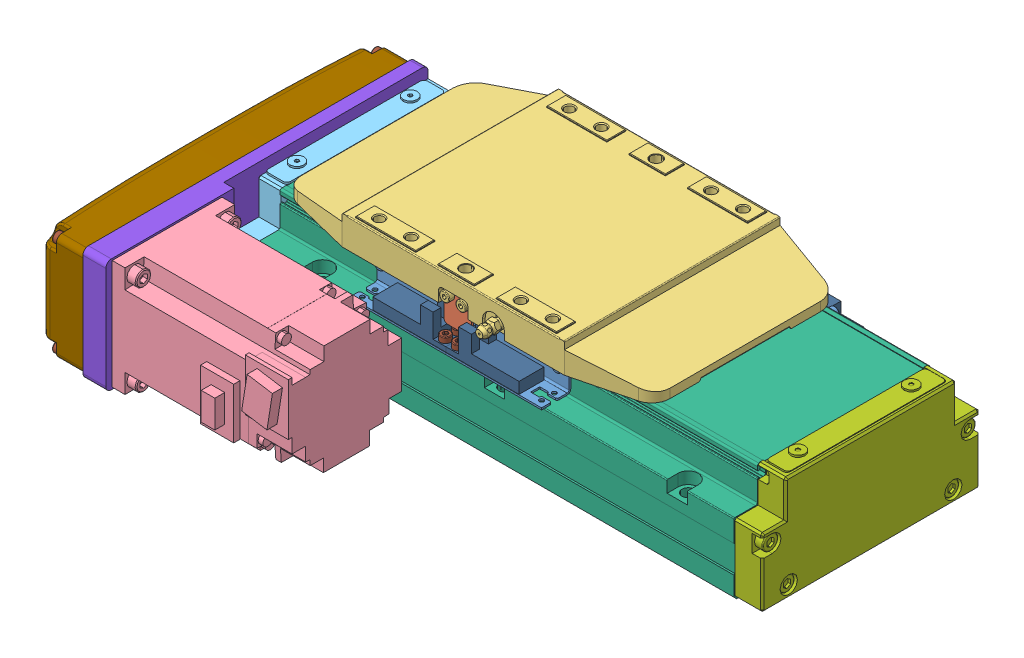
SolidWorks assembly G12-BL-400W, configuration Default. Lengths in mm.
Overall size (320.5 76 207.1).
25 component instances, 11 part files, 62 mates.
Components (placement in the parent):
- 304开关座片G5-12^G12-BL-400W-1: 304开关座片G5-12^G12-BL-400W [Default] at (209 38.5 -47.2) x (-1 0 0) z (0 0 -1) size (52.5 15.7 21) (virtual)
- 304开关座片G5-12^G12-BL-400W-2: 304开关座片G5-12^G12-BL-400W [Default] at (54 38.5 47.2) size (52.5 15.7 21) (virtual)
- 304开关座片G5-12^G12-BL-400W-3: 304开关座片G5-12^G12-BL-400W [Default] at (106.5 38.5 47.2) size (52.5 15.7 21) (virtual)
- 304感应片G8-12^G12-BL-400W-1: 304感应片G8-12^G12-BL-400W [Default] at (106.5 56.7 0) x (1 0 0) z (0 0 -1) size (15 17 1) (virtual)
- 304感应片G8-12^G12-BL-400W-2: 304感应片G8-12^G12-BL-400W [Default] at (106.5 56.7 0) x (-1 0 0) z (0 0 1) size (15 17 1) (virtual)
- 滑台G12^G12-BL-400W-1: 滑台G12^G12-BL-400W [Default] at (106.5 59.3 0) size (201.5 16.7 133.6) (virtual)
- 三菱400w^G12-BL-400W-1: 三菱400w^G12-BL-400W [Default] at (-7.5 32.5 101.5) x (0 0 1) z (0 1 0) size (68.8 128.3 60) (virtual)
- 丝杆座板G12^G12-BL-400W-1: 丝杆座板G12^G12-BL-400W [Default] at origin size (20.5 58.7 119) (virtual)
- 复件 复件 底座GY12+211^G12-BL-400W-1: 复件 复件 底座GY12+211^G12-BL-400W [默认] x (0 0 -1) z (1 0 0) size (120 58 261) (virtual)
- 塑胶轴承座G12^G12-BL-400W-2: 塑胶轴承座G12^G12-BL-400W [Default] at (261 0 0) size (15 58.9 119) (virtual)
- 电机板G12-BLR-P60^G12-BL-400W-1: 电机板G12-BLR-P60^G12-BL-400W [Default] at origin size (12.5 62 181.75) (virtual)
- 复件 同步轮罩壳G12^G12-BL-400W-1: 复件 同步轮罩壳G12^G12-BL-400W [默认] at (-43.3 32.5 44.125) x (0 0 1) z (0 1 0) size (180.75 24.5 61.51) (virtual)
- 复件 光电开关EE-SX674^G12-BL-400W-1: 复件 光电开关EE-SX674^G12-BL-400W [默认] at (66.5 41.8 49.4) size (40 15.5 13.6) (virtual)
- 复件 光电开关EE-SX674^G12-BL-400W-2: 复件 光电开关EE-SX674^G12-BL-400W [默认] at (146.5 41.8 63) x (-1 0 0) z (0 0 -1) size (40 15.5 13.6) (virtual)
- 复件 光电开关EE-SX674^G12-BL-400W-3: 复件 光电开关EE-SX674^G12-BL-400W [默认] at (196.5 41.8 -49.4) x (-1 0 0) z (0 0 -1) size (40 15.5 13.6) (virtual)
- hexagon socket head cap screws gb-1: hexagon socket head cap screws gb [GB_FASTENER_SCREWS_HSHCS M3X5-N] at (103 47.4 59.7) x (0 -1 0) z (0 0 1) size (8 5.5 5.5)
- hexagon socket head cap screws gb-2: hexagon socket head cap screws gb [GB_FASTENER_SCREWS_HSHCS M3X5-N] at (110 47.4 59.7) x (0 -1 0) z (0 0 1) size (8 5.5 5.5)
- hexagon socket head cap screws gb-3: hexagon socket head cap screws gb [GB_FASTENER_SCREWS_HSHCS M3X5-N] at (103 47.4 52.7) x (0 -1 0) z (0 0 1) size (8 5.5 5.5)
- hexagon socket head cap screws gb-4: hexagon socket head cap screws gb [GB_FASTENER_SCREWS_HSHCS M3X5-N] at (110 47.4 52.7) x (0 -1 0) z (0 0 1) size (8 5.5 5.5)
- hexagon socket head cap screws gb-6: hexagon socket head cap screws gb [GB_FASTENER_SCREWS_HSHCS M3X5-N] at (160 47.4 -59.7) x (0 -1 0) z (0 0 1) size (8 5.5 5.5)
- hexagon socket head cap screws gb-7: hexagon socket head cap screws gb [GB_FASTENER_SCREWS_HSHCS M3X5-N] at (160 47.4 -52.7) x (0 -1 0) z (0 0 1) size (8 5.5 5.5)
- hexagon socket head cap screws gb-8: hexagon socket head cap screws gb [GB_FASTENER_SCREWS_HSHCS M3X20-N] at (-38 58.5 131.125) size (23 5.5 5.5)
- hexagon socket head cap screws gb-9: hexagon socket head cap screws gb [GB_FASTENER_SCREWS_HSHCS M3X20-N] at (-38 6.5 131.125) size (23 5.5 5.5)
- hexagon socket head cap screws gb-10: hexagon socket head cap screws gb [GB_FASTENER_SCREWS_HSHCS M3X20-N] at (-38 6.5 -42.875) size (23 5.5 5.5)
- hexagon socket head cap screws gb-11: hexagon socket head cap screws gb [GB_FASTENER_SCREWS_HSHCS M3X20-N] at (-38 58.5 -42.875) size (23 5.5 5.5)
Mates (geometry in assembly coordinates):
- 宽度3: width: plane of 丝杆座板G12^G12-BL-400W-1 through (-13 37.5 59.5) normal (0 0 1); plane of 丝杆座板G12^G12-BL-400W-1 through (-13 2 -59.5) normal (0 0 -1); plane of 复件 复件 底座GY12+211^G12-BL-400W-1 through (261 12.5 -59.5) normal (0 0 -1); plane of 复件 复件 底座GY12+211^G12-BL-400W-1 through (261 26.5 59.5) normal (0 0 1)
- 距离2: distance = 1 mm: plane of 复件 复件 底座GY12+211^G12-BL-400W-1 through (261 0 58.5) normal (0 -1 0); plane of 丝杆座板G12^G12-BL-400W-1 through (-13 1 58.5) normal (0 -1 0)
- 重合11: coincident: plane of 丝杆座板G12^G12-BL-400W-1 through (0 0 0) normal (1 0 0); plane of 复件 复件 底座GY12+211^G12-BL-400W-1 through (0 57 46.2) normal (-1 0 0)
- 宽度8: width: plane of 滑台G12^G12-BL-400W-1 through (45.75 76 59) normal (0 0 1); plane of 滑台G12^G12-BL-400W-1 through (167.25 76 -59) normal (0 0 -1); plane of 复件 复件 底座GY12+211^G12-BL-400W-1 through (261 12.5 -59.5) normal (0 0 -1); plane of 复件 复件 底座GY12+211^G12-BL-400W-1 through (261 26.5 59.5) normal (0 0 1)
- 距离5: distance = 76 mm: plane of 滑台G12^G12-BL-400W-1 through (15.75 76 -41.214) normal (0 1 0); plane of 复件 复件 底座GY12+211^G12-BL-400W-1 through (261 0 58.5) normal (0 -1 0)
- 宽度9: width: plane of 304感应片G8-12^G12-BL-400W-2 through (99 64 56.5) normal (-1 0 0); plane of 304感应片G8-12^G12-BL-400W-2 through (114 51 56.5) normal (1 0 0); plane of 滑台G12^G12-BL-400W-1 through (98.5 65 55.5) normal (1 0 0); plane of 滑台G12^G12-BL-400W-1 through (114.5 59.3 55.5) normal (-1 0 0)
- 距离6: distance = 10.3 mm: plane of 304感应片G8-12^G12-BL-400W-2 through (101 49 56.5) normal (0 -1 0); plane of 滑台G12^G12-BL-400W-1 through (15.75 59.3 -41.214) normal (0 -1 0)
- 距离7: distance = 2.5 mm: plane of 304感应片G8-12^G12-BL-400W-2 through (112 51 56.5) normal (0 0 1); plane of 滑台G12^G12-BL-400W-1 through (45.75 76 59) normal (0 0 1)
- 宽度10: width: plane of 304感应片G8-12^G12-BL-400W-1 through (99 51 -56.5) normal (-1 0 0); plane of 304感应片G8-12^G12-BL-400W-1 through (114 64 -56.5) normal (1 0 0); plane of 滑台G12^G12-BL-400W-1 through (98.5 65 -55.5) normal (1 0 0); plane of 滑台G12^G12-BL-400W-1 through (114.5 59.3 -55.5) normal (-1 0 0)
- 距离8: distance = 2.5 mm: plane of 304感应片G8-12^G12-BL-400W-1 through (101 51 -56.5) normal (0 0 -1); plane of 滑台G12^G12-BL-400W-1 through (167.25 76 -59) normal (0 0 -1)
- 距离9: distance = 10.3 mm: plane of 304感应片G8-12^G12-BL-400W-1 through (112 49 -56.5) normal (0 -1 0); plane of 滑台G12^G12-BL-400W-1 through (15.75 59.3 -41.214) normal (0 -1 0)
- 宽度14: width: plane of 塑胶轴承座G12^G12-BL-400W-2 through (276 37.5 59.5) normal (0 0 1); plane of 塑胶轴承座G12^G12-BL-400W-2 through (276 2 -59.5) normal (0 0 -1); plane of 复件 复件 底座GY12+211^G12-BL-400W-1 through (261 12.5 -59.5) normal (0 0 -1); plane of 复件 复件 底座GY12+211^G12-BL-400W-1 through (261 26.5 59.5) normal (0 0 1)
- 重合23: coincident: plane of 复件 复件 底座GY12+211^G12-BL-400W-1 through (261 57 46.2) normal (1 0 0); plane of 塑胶轴承座G12^G12-BL-400W-2 through (261 0 0) normal (-1 0 0)
- 距离10: distance = 1 mm: plane of 塑胶轴承座G12^G12-BL-400W-2 through (276 1 58.5) normal (0 -1 0); plane of 复件 复件 底座GY12+211^G12-BL-400W-1 through (261 0 58.5) normal (0 -1 0)
- 距离11: distance = 67 mm: plane of 304开关座片G5-12^G12-BL-400W-2 through (54 42.8 49.2) normal (-1 0 0); plane of 丝杆座板G12^G12-BL-400W-1 through (-13 0 0) normal (-1 0 0)
- 距离12: distance = 105 mm: plane of 304开关座片G5-12^G12-BL-400W-3 through (159 42.8 49.2) normal (1 0 0); plane of 304开关座片G5-12^G12-BL-400W-2 through (54 42.8 49.2) normal (-1 0 0)
- 宽度15: width: plane of 复件 复件 底座GY12+211^G12-BL-400W-1 through (261 51.25 46.2) normal (0 1 0); plane of 复件 复件 底座GY12+211^G12-BL-400W-1 through (261 54.75 46.7) normal (0 -1 0); cylinder of 304开关座片G5-12^G12-BL-400W-2 through (58 53 42.2) axis (0 0 -1) radius 2.75
- 重合28: coincident: plane of 304开关座片G5-12^G12-BL-400W-2 through (106.5 40.8 63.2) normal (0 -1 0); plane of 304开关座片G5-12^G12-BL-400W-3 through (159 40.8 63.2) normal (0 -1 0)
- 重合29: coincident: plane of 304开关座片G5-12^G12-BL-400W-2 through (106.5 56.5 48.2) normal (0 0 1); plane of 304开关座片G5-12^G12-BL-400W-3 through (159 56.5 48.2) normal (0 0 1)
- 重合30: coincident: plane of 304开关座片G5-12^G12-BL-400W-2 through (106.5 42.8 47.2) normal (0 0 -1); plane of 复件 复件 底座GY12+211^G12-BL-400W-1 through (261 50.75 47.2) normal (0 0 1)
- 宽度16: width: plane of 复件 复件 底座GY12+211^G12-BL-400W-1 through (261 51.25 -46.7) normal (0 1 0); plane of 复件 复件 底座GY12+211^G12-BL-400W-1 through (261 54.75 -46.2) normal (0 -1 0); cylinder of 304开关座片G5-12^G12-BL-400W-1 through (205 53 -42.2) axis (0 0 1) radius 2.75
- 重合36: coincident: plane of 304开关座片G5-12^G12-BL-400W-1 through (156.5 42.8 -47.2) normal (0 0 1); plane of 复件 复件 底座GY12+211^G12-BL-400W-1 through (261 40 -47.2) normal (0 0 -1)
- 距离15: distance = 12.75 mm: plane of 电机板G12-BLR-P60^G12-BL-400W-1 through (-59.5 4.5 -46.75) normal (0 0 -1); plane of 复件 复件 底座GY12+211^G12-BL-400W-1 through (261 12.5 -59.5) normal (0 0 -1)
- 距离16: distance = 1.5 mm: plane of 电机板G12-BLR-P60^G12-BL-400W-1 through (-59.5 1.5 132) normal (0 -1 0); plane of 复件 复件 底座GY12+211^G12-BL-400W-1 through (261 0 -35) normal (0 -1 0)
- 重合39: coincident: plane of 丝杆座板G12^G12-BL-400W-1 through (-13 0 0) normal (-1 0 0); plane of 电机板G12-BLR-P60^G12-BL-400W-1 through (-13 4.5 132) normal (1 0 0)
- 距离17: distance = 11.5 mm: plane of 三菱400w^G12-BL-400W-1 through (67 2.5 71.5) normal (0 0 -1); plane of 复件 复件 底座GY12+211^G12-BL-400W-1 through (261 38.5 60) normal (0 0 1)
- 宽度22: width: plane of 电机板G12-BLR-P60^G12-BL-400W-1 through (-59.5 1.5 132) normal (0 -1 0); plane of 电机板G12-BLR-P60^G12-BL-400W-1 through (-59.5 63.5 -43.75) normal (0 1 0); plane of 三菱400w^G12-BL-400W-1 through (67 62.5 71.5) normal (0 1 0); plane of 三菱400w^G12-BL-400W-1 through (67 2.5 131.5) normal (0 -1 0)
- 重合43: coincident: plane of 三菱400w^G12-BL-400W-1 through (-7.5 32.5 101.5) normal (-1 0 0); plane of 电机板G12-BLR-P60^G12-BL-400W-1 through (-7.5 4.5 132) normal (1 0 0)
- 宽度23: width: plane of 304开关座片G5-12^G12-BL-400W-2 through (54 42.8 49.2) normal (-1 0 0); plane of 304开关座片G5-12^G12-BL-400W-3 through (159 42.8 49.2) normal (1 0 0); plane of 304感应片G8-12^G12-BL-400W-2 through (99 64 56.5) normal (-1 0 0); plane of 304感应片G8-12^G12-BL-400W-2 through (114 51 56.5) normal (1 0 0)
- 距离18: distance = 67 mm: plane of 304开关座片G5-12^G12-BL-400W-1 through (209 42.8 -49.2) normal (1 0 0); plane of 塑胶轴承座G12^G12-BL-400W-2 through (276 0 0) normal (1 0 0)
- 重合44: coincident: plane of 304开关座片G5-12^G12-BL-400W-2 through (106.5 41.8 49.2) normal (0 1 0); plane of 复件 光电开关EE-SX674^G12-BL-400W-1 through (106.5 41.8 63) normal (0 -1 0)
- 同心7: concentric: cylinder of 304开关座片G5-12^G12-BL-400W-2 through (103 43.5 52.7) axis (0 -1 0) radius 1.23; cylinder of 复件 光电开关EE-SX674^G12-BL-400W-1 through (103 30.8 52.7) axis (0 1 0) radius 1.75
- 同心8: concentric: cylinder of 304开关座片G5-12^G12-BL-400W-2 through (103 43.5 59.7) axis (0 -1 0) radius 1.23; cylinder of 复件 光电开关EE-SX674^G12-BL-400W-1 through (103 30.8 59.7) axis (0 1 0) radius 1.75
- 同心9: concentric: cylinder of 304开关座片G5-12^G12-BL-400W-3 through (110 43.5 59.7) axis (0 -1 0) radius 1.23; cylinder of 复件 光电开关EE-SX674^G12-BL-400W-2 through (110 30.8 59.7) axis (0 1 0) radius 1.75
- 重合45: coincident: plane of 304开关座片G5-12^G12-BL-400W-3 through (159 41.8 49.2) normal (0 1 0); plane of 复件 光电开关EE-SX674^G12-BL-400W-2 through (106.5 41.8 49.4) normal (0 -1 0)
- 同心10: concentric: cylinder of 304开关座片G5-12^G12-BL-400W-3 through (110 43.5 52.7) axis (0 -1 0) radius 1.23; cylinder of 复件 光电开关EE-SX674^G12-BL-400W-2 through (110 30.8 52.7) axis (0 1 0) radius 1.75
- 重合46: coincident: plane of 304开关座片G5-12^G12-BL-400W-1 through (156.5 41.8 -49.2) normal (0 1 0); plane of 复件 光电开关EE-SX674^G12-BL-400W-3 through (156.5 41.8 -63) normal (0 -1 0)
- 同心11: concentric: cylinder of 304开关座片G5-12^G12-BL-400W-1 through (160 43.5 -59.7) axis (0 -1 0) radius 1.23; cylinder of 复件 光电开关EE-SX674^G12-BL-400W-3 through (160 30.8 -59.7) axis (0 1 0) radius 1.75
- 同心12: concentric: cylinder of 304开关座片G5-12^G12-BL-400W-1 through (160 43.5 -52.7) axis (0 -1 0) radius 1.23; cylinder of 复件 光电开关EE-SX674^G12-BL-400W-3 through (160 30.8 -52.7) axis (0 1 0) radius 1.75
- 同心161: concentric: cylinder of 复件 光电开关EE-SX674^G12-BL-400W-1 through (103 30.8 59.7) axis (0 1 0) radius 1.75; cylinder of hexagon socket head cap screws gb-1 through (103 39.4 59.7) axis (0 1 0) radius 1.5
- 重合501: coincident: plane of 复件 光电开关EE-SX674^G12-BL-400W-1 through (99.5 44.4 63) normal (0 1 0); plane of hexagon socket head cap screws gb-1 through (103 44.4 59.7) normal (0 -1 0)
- 同心171: concentric: cylinder of 复件 光电开关EE-SX674^G12-BL-400W-2 through (110 30.8 59.7) axis (0 1 0) radius 1.75; cylinder of hexagon socket head cap screws gb-2 through (110 39.4 59.7) axis (0 1 0) radius 1.5
- 重合511: coincident: plane of 复件 光电开关EE-SX674^G12-BL-400W-2 through (113.5 44.4 49.4) normal (0 1 0); plane of hexagon socket head cap screws gb-2 through (110 44.4 59.7) normal (0 -1 0)
- 同心181: concentric: cylinder of 复件 光电开关EE-SX674^G12-BL-400W-1 through (103 30.8 52.7) axis (0 1 0) radius 1.75; cylinder of hexagon socket head cap screws gb-3 through (103 39.4 52.7) axis (0 1 0) radius 1.5
- 重合521: coincident: plane of 复件 光电开关EE-SX674^G12-BL-400W-1 through (99.5 44.4 63) normal (0 1 0); plane of hexagon socket head cap screws gb-3 through (103 44.4 52.7) normal (0 -1 0)
- 同心191: concentric: cylinder of 复件 光电开关EE-SX674^G12-BL-400W-2 through (110 30.8 52.7) axis (0 1 0) radius 1.75; cylinder of hexagon socket head cap screws gb-4 through (110 39.4 52.7) axis (0 1 0) radius 1.5
- 重合531: coincident: plane of 复件 光电开关EE-SX674^G12-BL-400W-2 through (113.5 44.4 49.4) normal (0 1 0); plane of hexagon socket head cap screws gb-4 through (110 44.4 52.7) normal (0 -1 0)
- 同心211: concentric: cylinder of 复件 光电开关EE-SX674^G12-BL-400W-3 through (160 30.8 -59.7) axis (0 1 0) radius 1.75; cylinder of hexagon socket head cap screws gb-6 through (160 39.4 -59.7) axis (0 1 0) radius 1.5
- 重合551: coincident: plane of 复件 光电开关EE-SX674^G12-BL-400W-3 through (163.5 44.4 -63) normal (0 1 0); plane of hexagon socket head cap screws gb-6 through (160 44.4 -59.7) normal (0 -1 0)
- 同心221: concentric: cylinder of 复件 光电开关EE-SX674^G12-BL-400W-3 through (160 30.8 -52.7) axis (0 1 0) radius 1.75; cylinder of hexagon socket head cap screws gb-7 through (160 39.4 -52.7) axis (0 1 0) radius 1.5
- 重合561: coincident: plane of 复件 光电开关EE-SX674^G12-BL-400W-3 through (163.5 44.4 -63) normal (0 1 0); plane of hexagon socket head cap screws gb-7 through (160 44.4 -52.7) normal (0 -1 0)
- 重合562: coincident: plane of 电机板G12-BLR-P60^G12-BL-400W-1 through (-20 -100 200) normal (-1 0 0); plane of 复件 同步轮罩壳G12^G12-BL-400W-1 through (-20 32.5 44.125) normal (1 0 0)
- 同心222: concentric: cylinder of 复件 同步轮罩壳G12^G12-BL-400W-1 through (-44.5 58.5 -42.875) axis (-1 0 0) radius 1.7; cylinder of hexagon socket head cap screws gb-11 through (-35 58.5 -42.875) axis (-1 0 0) radius 2.75
- 重合563: coincident: plane of 复件 同步轮罩壳G12^G12-BL-400W-1 through (-35 58.5 -41.175) normal (-1 0 0); circle of hexagon socket head cap screws gb-11
- 同心223: concentric: cylinder of 复件 同步轮罩壳G12^G12-BL-400W-1 through (-44.5 6.5 -42.875) axis (-1 0 0) radius 1.7; cylinder of hexagon socket head cap screws gb-10 through (-35 6.5 -42.875) axis (-1 0 0) radius 2.75
- 重合564: coincident: plane of 复件 同步轮罩壳G12^G12-BL-400W-1 through (-35 6.5 -41.175) normal (-1 0 0); circle of hexagon socket head cap screws gb-10
- 同心224: concentric: cylinder of 复件 同步轮罩壳G12^G12-BL-400W-1 through (-44.5 58.5 131.125) axis (-1 0 0) radius 1.7; cylinder of hexagon socket head cap screws gb-8 through (-35 58.5 131.125) axis (-1 0 0) radius 2.75
- 重合565: coincident: plane of 复件 同步轮罩壳G12^G12-BL-400W-1 through (-35 58.5 132.825) normal (-1 0 0); circle of hexagon socket head cap screws gb-8
- 同心225: concentric: cylinder of 复件 同步轮罩壳G12^G12-BL-400W-1 through (-44.5 6.5 131.125) axis (-1 0 0) radius 1.7; cylinder of hexagon socket head cap screws gb-9 through (-35 6.5 131.125) axis (-1 0 0) radius 2.75
- 重合566: coincident: plane of 复件 同步轮罩壳G12^G12-BL-400W-1 through (-35 6.5 132.825) normal (-1 0 0); circle of hexagon socket head cap screws gb-9
- 宽度24: width: plane of 电机板G12-BLR-P60^G12-BL-400W-1 through (-59.5 60.5 135) normal (0 0 1); plane of 电机板G12-BLR-P60^G12-BL-400W-1 through (-59.5 4.5 -46.75) normal (0 0 -1); plane of 复件 同步轮罩壳G12^G12-BL-400W-1 through (-20 63.25 134.5) normal (0 0 1); plane of 复件 同步轮罩壳G12^G12-BL-400W-1 through (-20 63.25 -46.25) normal (0 0 -1)
- 对称1: symmetric: plane of 电机板G12-BLR-P60^G12-BL-400W-1 through (-59.5 63.5 -43.75) normal (0 1 0); plane of 电机板G12-BLR-P60^G12-BL-400W-1 through (-59.5 1.5 132) normal (0 -1 0); plane of 复件 同步轮罩壳G12^G12-BL-400W-1 through (-43.3 32.5 44.125) normal (0 1 0)
